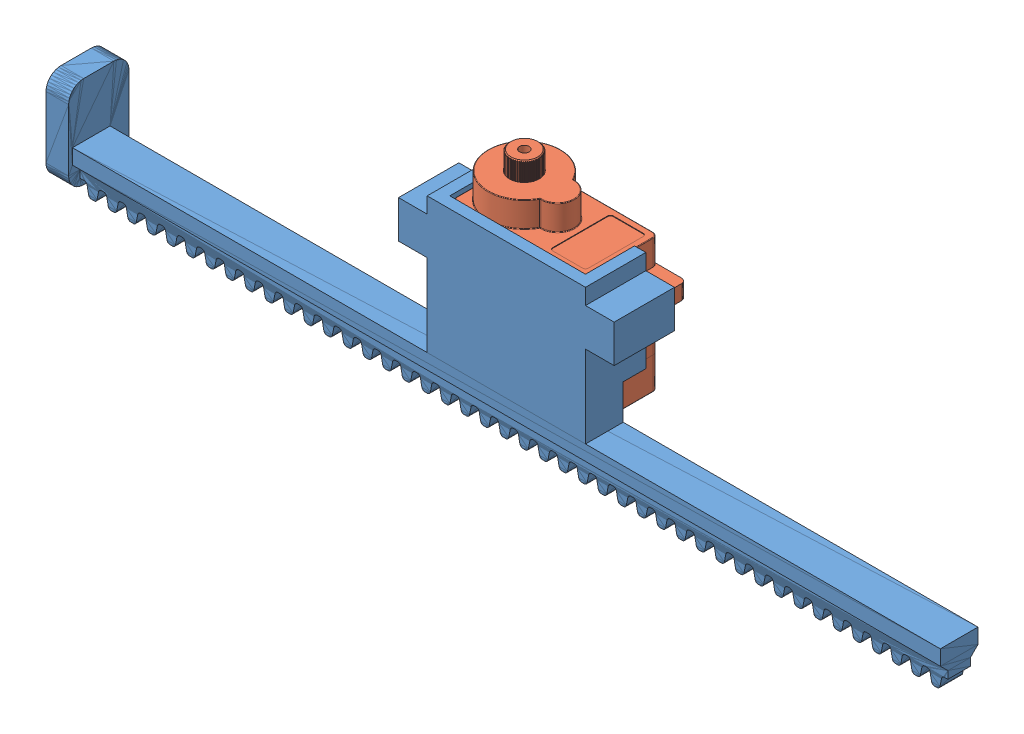
SolidWorks assembly pusherWithMotor, configuration Default. Lengths in mm.
Overall size (150 37.05 14.84).
2 component instances, 2 part files, 3 mates.
Components (placement in the parent):
- custompusher-1: custompusher [Default] at (-4.2932 62.7024 97.2008) size (150 30.06 10.79)
- SG90 - Micro Servo 9g - Tower Pro.1-1: SG90 - Micro Servo 9g - Tower Pro.1 [Peça] at (72.7918 88.4924 98.7208) size (32.1 29.95 12.4)
Mates (geometry in assembly coordinates):
- Coincident1: coincident anti-aligned: plane of custompusher-1 through (-4.2932 62.7024 104.8208) normal (0 0 -1); plane of SG90 - Micro Servo 9g - Tower Pro.1-1 through (62.3918 93.6424 104.8208) normal (0 0 1)
- Coincident2: coincident anti-aligned: plane of custompusher-1 through (-4.2932 77.9424 97.2008) normal (0 1 0); plane of SG90 - Micro Servo 9g - Tower Pro.1-1 through (62.3918 77.9424 103.9708) normal (0 -1 0)
- Coincident3: coincident anti-aligned: plane of custompusher-1 through (84.0418 62.7024 104.8208) normal (-1 0 0); plane of SG90 - Micro Servo 9g - Tower Pro.1-1 through (84.0418 77.9424 93.4708) normal (1 0 0)
